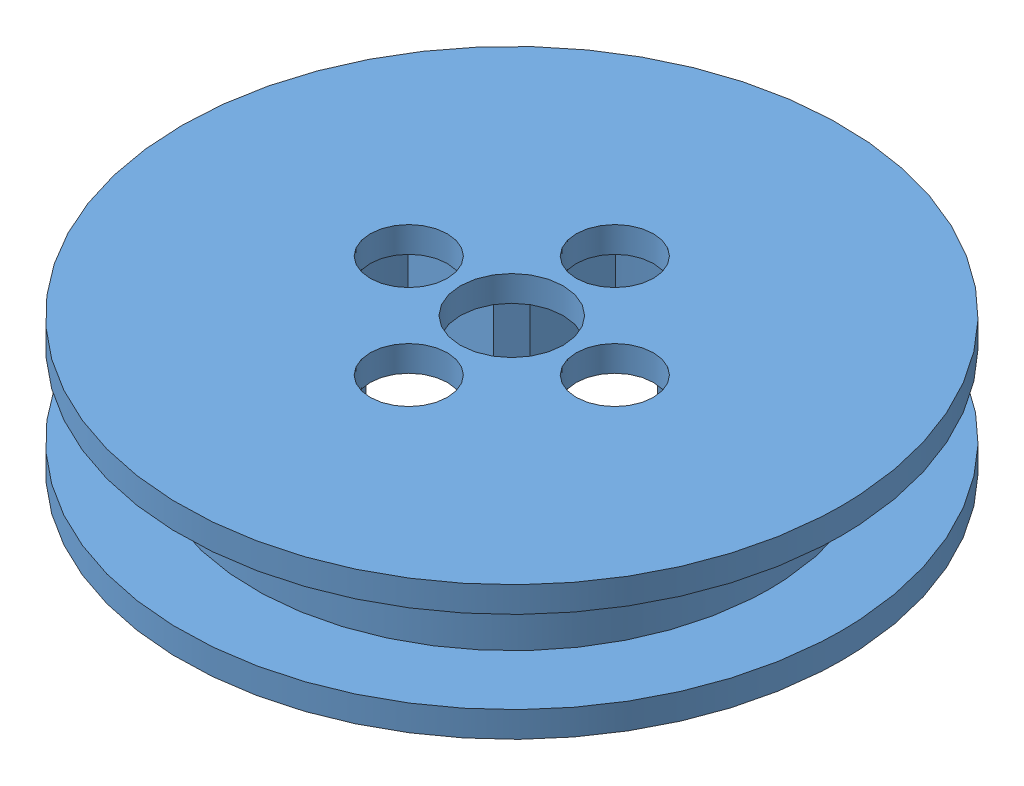
SolidWorks assembly motor_mount, configuration Default. Lengths in mm.
Overall size (95.24 76.05 365.35).
2 component instances, 2 part files, 4 mates.
Components (placement in the parent):
- spool-1: spool [Default] at (-119.4065 -42.838 332.5837) size (40.64 8.25 40.64)
- Part1^motor_mount-1: Part1^motor_mount [Default] at origin (virtual)
Mates (geometry in assembly coordinates):
- InPlace1: in place: plane of Part1^motor_mount-1 through (0 0 0) normal (0 0 1); moOrthogonalPlaneRef_w of Part1^motor_mount-1 through (0 0 0) normal (0 1 0); plane of Part1^motor_mount-1 through (0 0 0) normal (1 0 0); unknown of Part1^motor_mount-1
- Coincident1: coincident aligned: 
- Coincident2: coincident aligned: plane of Part1^Assem1-1 through (0 0 0) normal (0 1 0)
- Coincident3: coincident anti-aligned: plane of Part1^Assem1-1 through (0 0 0) normal (1 0 0)
